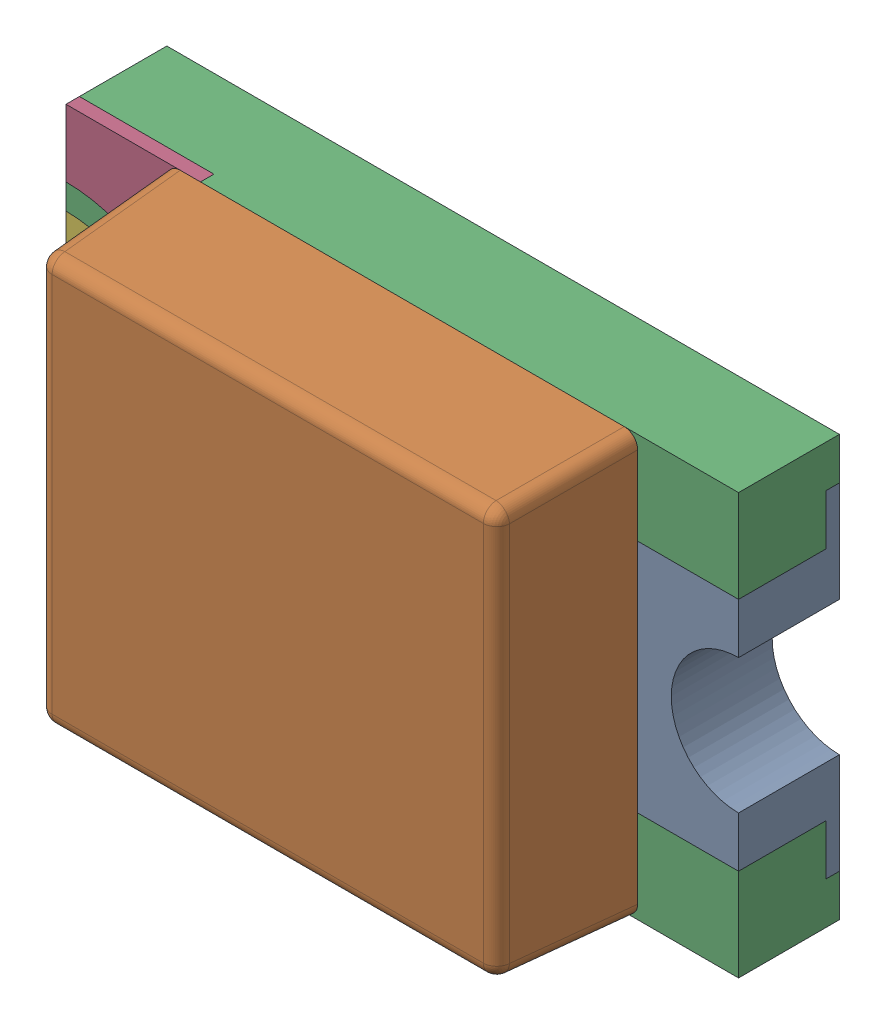
SolidWorks assembly D10, configuration Standard. Lengths in mm.
Overall size (2 1.25 0.7).
7 component instances, 5 part files, 0 mates.
Components (placement in the parent):
- WL-SMCW_0805_LED-1: WL-SMCW_0805_LED [Standard] at (12.1102 14.6502 -0.02) x (1 0 0) z (0 0 1) size (2 1.25 0.7)
  - base-1: base [Standard] at (0.8 0 0) x (-1 0 0) z (0 0 1) size (0.4 1 0.3)
  - cover-1: cover [Standard] at (0 0 0.3) size (1.4 1.25 0.4)
  - housing_3-1: housing_3 [Standard] at origin size (2 1.25 0.3)
  - marking-1: marking [Standard] at (-0.8 0.525 0.26) size (0.4 0.48 0.04)
  - marking-2: marking [Standard] at (-0.8 -0.525 0.3) x (1 0 0) z (0 0 -1) size (0.4 0.48 0.04)
  - base_2-1: base_2 [Standard] at (-0.8 0 0) size (0.4 1 0.3)
